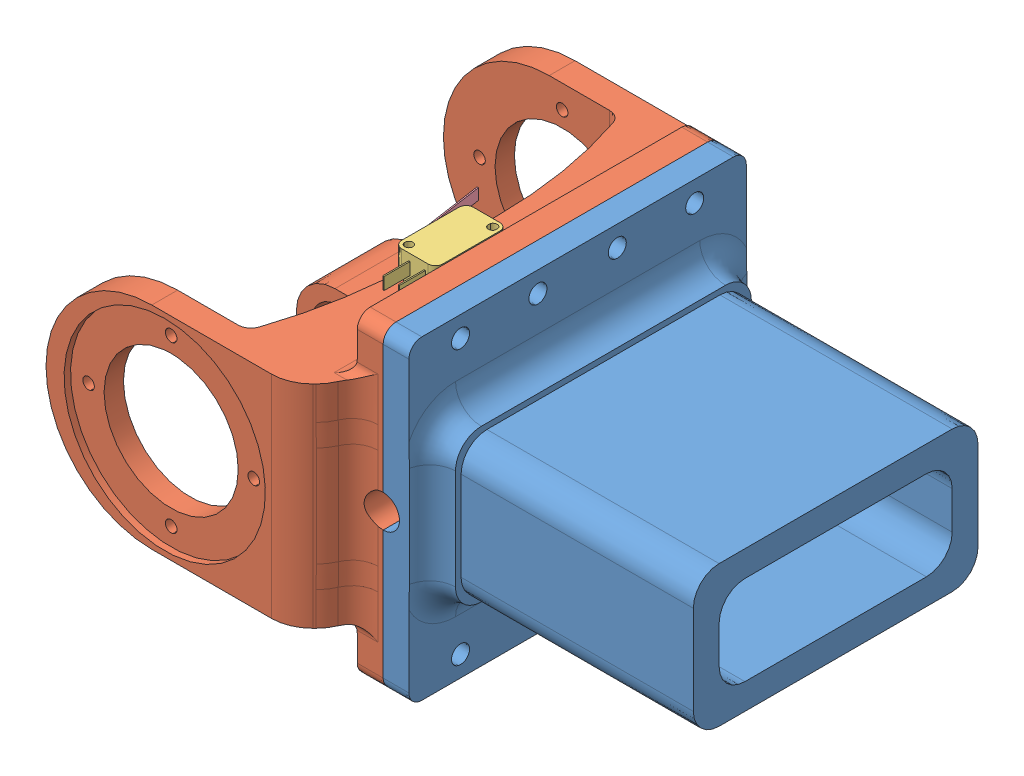
SolidWorks assembly Input frame_separated, configuration Default. Lengths in mm.
Overall size (224 122 164).
8 component instances, 4 part files, 9 mates.
Components (placement in the parent):
- Wrist input frame_CF insert-1: Wrist input frame_CF insert [Default] at (49.0789 -40.8048 -20.3361) size (110.43 122 130.75)
- Wrist input frame_attachment-1: Wrist input frame_attachment [Default] at (29.0789 -40.8048 -20.3361) size (114 122 164)
- V_152_1C25-1: V_152_1C25 [Default] at (-14.6406 117.8584 123.0335) x (0 0 1) z (0 -1 0) size (48.18 24.9 10.3)
  - V_152_1C25_BASE-1: V_152_1C25_BASE [Default] at origin size (37.8 20.43 10.3)
  - V_152_1C25_ACTUATOR-1: V_152_1C25_ACTUATOR [Default] at (-8.6 2.8 -0.2) size (27.28 6.1 4.3)
- V_152_1C25-2: V_152_1C25 [Default] at (-14.6406 25.5584 123.0335) x (0 0 1) z (0 -1 0) size (48.18 24.9 10.3)
  - V_152_1C25_BASE-1: V_152_1C25_BASE [Default] at origin size (37.8 20.43 10.3)
  - V_152_1C25_ACTUATOR-1: V_152_1C25_ACTUATOR [Default] at (-8.6 2.8 -0.2) size (27.28 6.1 4.3)
Mates (geometry in assembly coordinates):
- Concentric1: concentric anti-aligned: cylinder of Wrist input frame_attachment-1 through (-14.6406 112.7084 123.0335) axis (0 1 0) radius 1.5; cylinder of V_152_1C25-1/V_152_1C25_BASE-1 through (-14.6406 123.0084 123.0335) axis (0 -1 0) radius 1.55
- Concentric2: concentric anti-aligned: cylinder of Wrist input frame_attachment-1 through (-4.3406 112.7084 100.8335) axis (0 1 0) radius 1.5; cylinder of V_152_1C25-1/V_152_1C25_BASE-1 through (-4.3406 123.0084 100.8335) axis (0 -1 0) radius 1.7
- Coincident4: coincident anti-aligned: plane of Wrist input frame_attachment-1 through (8.5594 112.7084 100.8335) normal (0 1 0); plane of V_152_1C25-1/V_152_1C25_BASE-1 through (-17.4406 112.7084 98.0335) normal (0 -1 0)
- Concentric3: concentric anti-aligned: cylinder of Wrist input frame_CF insert-1 through (28.5594 124.7084 146.2061) axis (1 0 0) radius 3.5; circle of Wrist input frame_attachment-1
- Concentric4: concentric anti-aligned: cylinder of Wrist input frame_CF insert-1 through (28.5594 124.7084 55.4609) axis (1 0 0) radius 3.5; cylinder of Wrist input frame_attachment-1 through (8.5594 124.7084 55.4609) axis (-1 0 0) radius 3.5
- Coincident5: coincident anti-aligned: plane of Wrist input frame_CF insert-1 through (18.5594 -40.8048 -20.3361) normal (-1 0 0); plane of Wrist input frame_attachment-1 through (18.5594 -40.8048 -20.3361) normal (1 0 0)
- Concentric5: concentric aligned: cylinder of Wrist input frame_attachment-1 through (-14.6406 30.7084 123.0335) axis (0 -1 0) radius 1.5; cylinder of V_152_1C25-2/V_152_1C25_BASE-1 through (-14.6406 30.7084 123.0335) axis (0 -1 0) radius 1.55
- Concentric6: concentric aligned: cylinder of Wrist input frame_attachment-1 through (-4.3406 30.7084 100.8335) axis (0 -1 0) radius 1.5; cylinder of V_152_1C25-2/V_152_1C25_BASE-1 through (-4.3406 30.7084 100.8335) axis (0 -1 0) radius 1.7
- Coincident6: coincident anti-aligned: plane of Wrist input frame_attachment-1 through (8.5594 30.7084 100.8335) normal (0 -1 0); plane of V_152_1C25-2/V_152_1C25_BASE-1 through (-17.4406 30.7084 98.0335) normal (0 1 0)
